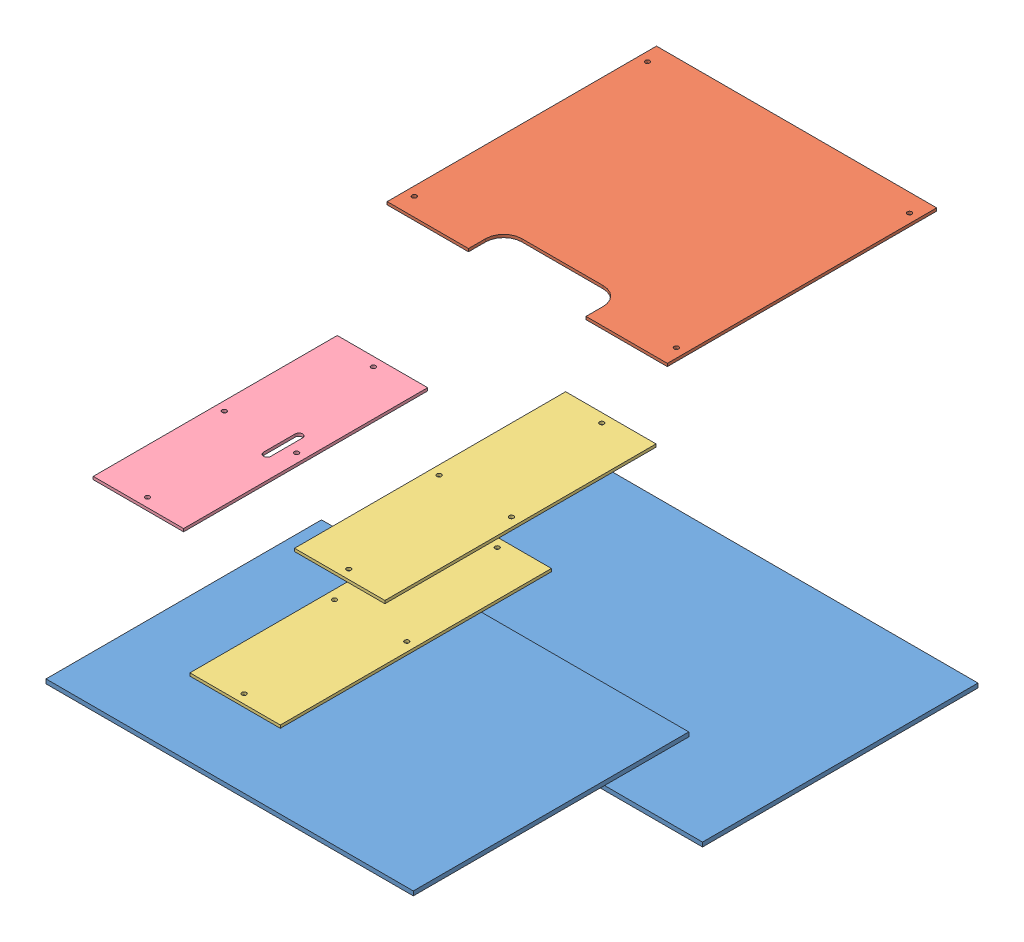
SolidWorks assembly Assem1, configuration Default. Lengths in mm.
Overall size (407.3 440.01 623.88).
6 component instances, 4 part files, 7 mates.
Components (placement in the parent):
- stock-1: stock [Default] at (-34.4581 117.0174 626.2767) x (1 0 0) z (0 -1 0) size (406.4 304.8 4.76)
- stock-2: stock [Default] at (-33.5621 4.7625 307.1931) x (1 0 0) z (0 -1 0) size (406.4 304.8 4.76)
- bottom_cover_plate-1: bottom_cover_plate [Default] at (329.9118 436.8324 628.9841) x (0 0 -1) z (1 0 0) size (298 3.17 310)
- Side_Plate_1-1: Side_Plate_1 [Default] at (340.1789 376.1764 930.7494) x (0 0 -1) z (1 0 0) size (300 3.17 100)
- Side_Plates_2-1: Side_Plates_2 [Default] at (0 316.2174 643.265) x (0 0 1) z (-1 0 0) size (270 3.17 100)
- Side_Plate_1-2: Side_Plate_1 [Default] at (122.3211 196.825 628.6257) x (0 0 1) z (-1 0 0) size (300 3.17 100)
Mates (geometry in assembly coordinates):
- Parallel1: parallel anti-aligned: plane of stock-1 through (-34.4581 112.2549 626.2767) normal (0 -1 0)
- Coincident1: coincident anti-aligned: plane of stock-2 through (-33.5621 0 307.1931) normal (0 -1 0)
- Parallel2: parallel anti-aligned: plane of bottom_cover_plate-1 through (329.9118 436.8324 628.9841) normal (0 0 -1)
- Parallel3: parallel anti-aligned: plane of Side_Plate_1-1 through (340.1789 376.1764 930.7494) normal (0 0 -1)
- Coincident4: coincident anti-aligned: plane of Side_Plates_2-1 through (0 316.2174 643.265) normal (-1 0 0)
- Parallel4: parallel anti-aligned: plane of Side_Plate_1-2 through (122.3211 196.825 628.6257) normal (-1 0 0)
- Distance1: distance = 200 mm aligned: plane of Side_Plate_1-2 through (122.3211 200 628.6257) normal (0 1 0)
